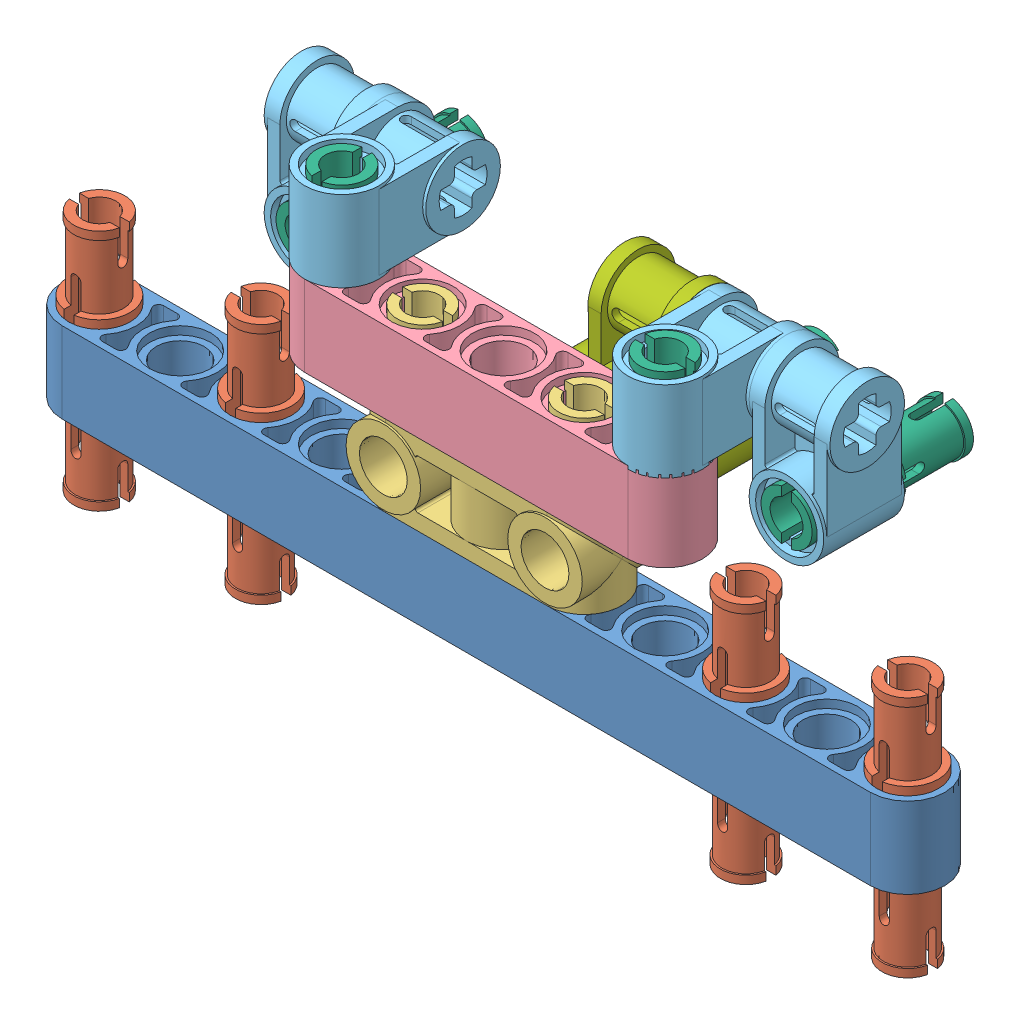
SolidWorks assembly NXT Mount LH, configuration Default. Lengths in mm.
Overall size (88.09 40.29 24.07).
17 component instances, 7 part files, 43 mates.
Components (placement in the parent):
- beam_11-1: beam_11 [Default] at (-40.325 -4.0325 0) size (88.09 8.06 7.44)
- conn_3-1: conn_3 [Default] at (24.195 0.0325 0) size (6.15 24.2 6.07)
- conn_3-2: conn_3 [Default] at (40.325 0.0325 0) x (-1 0 0) z (0 0 -1) size (6.15 24.2 6.07)
- conn_3-3: conn_3 [Default] at (-40.325 0.0325 0) size (6.15 24.2 6.07)
- conn_3-4: conn_3 [Default] at (-24.195 0.0325 0) size (6.15 24.2 6.07)
- conn_3w-1: conn_3w [Default] at (0 8.065 -3.72) x (0 1 0) z (1 0 0) size (24.2 7.85 23.57)
- beam_5-1: beam_5 [Default] at (-16.13 20.1625 0) x (1 0 0) z (0 0 -1) size (39.7 8.06 7.44)
- crossblock_2-1: crossblock_2 [Default] at (-24.195 20.1625 -11.785) x (0 1 0) z (1 0 0) size (15.5 8.06 8.06)
- crossblock_2-2: crossblock_2 [Default] at (16.13 20.1625 -4.0325) x (0 0 -1) z (1 0 0) size (15.5 8.06 8.06)
- crossblock_2-3: crossblock_2 [Default] at (-16.13 20.475 -4.0325) x (0 0 -1) z (1 0 0) size (15.5 8.06 8.06)
- crossblock_2-4: crossblock_2 [Default] at (24.195 19.85 -11.785) x (0 1 0) z (1 0 0) size (15.5 8.06 8.06)
- conn-1: conn [Default] at (24.195 15.8175 -12.0975) x (0 1 0) z (1 0 0) size (6.15 16.1 6.07)
- conn-2: conn [Default] at (-16.13 20.1625 0) x (0 0 1) z (1 0 0) size (6.15 16.1 6.07)
- conn-3: conn [Default] at (16.13 20.1625 0) size (6.15 16.1 6.07)
- conn-4: conn [Default] at (-24.195 16.13 -12.0975) x (0 1 0) z (1 0 0) size (6.15 16.1 6.07)
- crossblock-1: crossblock [Default] at (8.065 15.8175 -8.065) x (1 0 0) z (0 -1 0) size (15.5 8.06 15.51)
- conn-5: conn [Default] at (12.0975 15.8175 -11.3708) x (0.865085 0.501625 0) z (0.501625 -0.865085 0) size (6.15 16.1 6.07)
Mates (geometry in assembly coordinates):
- Concentric54: concentric anti-aligned: cylinder of beam_11-1 through (-8.065 -3.2175 0) axis (0 1 0) radius 2.39; cylinder of conn_3w-1 through (-8.065 3.2175 0) axis (0 -1 0) radius 2.39
- Concentric55: concentric anti-aligned: cylinder of beam_11-1 through (8.065 -3.2175 0) axis (0 1 0) radius 2.39; cylinder of conn_3w-1 through (8.065 3.2175 0) axis (0 -1 0) radius 2.39
- Coincident53: coincident anti-aligned: plane of beam_11-1 through (-45.8068 4.0325 3.8688) normal (0 1 0); plane of conn_3w-1 through (-12.2603 4.0325 -3.8688) normal (0 -1 0)
- Coincident141: coincident anti-aligned: circle of beam_11-1; circle of conn_3-2
- Coincident142: coincident anti-aligned: circle of beam_11-1; circle of conn_3-1
- Coincident143: coincident anti-aligned: circle of beam_11-1; circle of conn_3-4
- Coincident144: coincident anti-aligned: circle of beam_11-1; circle of conn_3-3
- Parallel68: parallel anti-aligned: plane of beam_11-1 through (-40.325 -4.0325 0) normal (0 0 1); plane of conn_3-2 through (40.325 0.0325 0) normal (0 0 -1)
- Parallel69: parallel aligned: plane of beam_11-1 through (-40.325 -4.0325 0) normal (0 0 1); plane of conn_3-3 through (-40.325 0.0325 0) normal (0 0 1)
- Parallel70: parallel aligned: plane of beam_11-1 through (-40.325 -4.0325 0) normal (0 0 1); plane of conn_3-4 through (-24.195 0.0325 0) normal (0 0 1)
- Concentric56: concentric aligned: cylinder of beam_5-1 through (-8.065 19.3475 0) axis (0 -1 0) radius 2.39; cylinder of conn_3w-1 through (-8.065 19.3475 0) axis (0 -1 0) radius 2.39
- Concentric57: concentric aligned: cylinder of conn_3w-1 through (8.065 19.3475 0) axis (0 -1 0) radius 2.39; cylinder of beam_5-1 through (8.065 19.3475 0) axis (0 -1 0) radius 2.39
- Coincident54: coincident anti-aligned: plane of conn_3w-1 through (12.2603 12.0975 -3.8688) normal (0 1 0); plane of beam_5-1 through (-20.6501 12.0975 -3.8688) normal (0 -1 0)
- Parallel14: parallel aligned: plane of conn_3w-1 through (12.2564 4.1962 -3.925) normal (0 0 -1); plane of crossblock_2-4 through (28.0677 11.9487 -12.0975) normal (0 0 -1)
- Parallel15: parallel aligned: plane of conn_3w-1 through (12.2564 4.1962 -3.925) normal (0 0 -1); plane of crossblock_2-1 through (-20.3223 12.2612 -12.0975) normal (0 0 -1)
- Parallel17: parallel aligned: plane of conn_3w-1 through (12.2564 4.1962 -3.925) normal (0 0 -1); plane of crossblock-1 through (-0.0013 11.9478 -12.0975) normal (0 0 -1)
- Concentric71: concentric anti-aligned: cylinder of beam_5-1 through (16.13 19.3475 0) axis (0 -1 0) radius 2.39; cylinder of crossblock_2-2 through (16.13 20.665 0) axis (0 1 0) radius 2.39
- Coincident71: coincident anti-aligned: plane of beam_5-1 through (-20.6501 20.1625 -3.8688) normal (0 1 0); plane of crossblock_2-2 through (19.9988 20.1625 0.1613) normal (0 -1 0)
- Concentric72: concentric anti-aligned: cylinder of beam_5-1 through (-16.13 19.3475 0) axis (0 -1 0) radius 2.39; cylinder of crossblock_2-3 through (-16.13 20.9775 0) axis (0 1 0) radius 2.39
- Coincident72: coincident anti-aligned: plane of beam_5-1 through (-20.6501 20.1625 -3.8688) normal (0 1 0); plane of crossblock_2-3 through (-12.2573 20.1625 3.8688) normal (0 -1 0)
- Coincident166: coincident anti-aligned: circle of beam_5-1; circle of conn-3
- Coincident167: coincident aligned: circle of beam_5-1; circle of conn-2
- Concentric74: concentric anti-aligned: circle of crossblock_2-1; circle of crossblock_2-3
- Coincident78: coincident anti-aligned: plane of crossblock_2-1 through (-20.1625 20.3262 -11.9377) normal (1 0 0); plane of crossblock_2-3 through (-20.1625 20.3223 -4.1962) normal (-1 0 0)
- Coincident160: coincident aligned: circle of crossblock_2-1; circle of conn-4
- Parallel13: parallel anti-aligned: plane of crossblock_2-2 through (12.0975 20.0098 -4.1962) normal (-1 0 0); plane of crossblock_2-3 through (-12.0975 20.3223 -4.1962) normal (1 0 0)
- Concentric73: concentric anti-aligned: circle of crossblock_2-2; circle of crossblock_2-4
- Coincident75: coincident anti-aligned: plane of crossblock_2-2 through (20.1625 20.0098 -4.1962) normal (1 0 0); plane of crossblock_2-4 through (20.1625 20.0137 -11.9377) normal (-1 0 0)
- Coincident79: coincident aligned: cylinder of conn-3 through (16.13 12.9275 0) axis (0 1 0) radius 2.39; circle of crossblock_2-2
- Concentric82: concentric aligned: circle of crossblock_2-2; circle of crossblock-1
- Coincident81: coincident anti-aligned: plane of crossblock_2-2 through (12.0975 20.0098 -4.1962) normal (-1 0 0); plane of crossblock-1 through (12.0975 20.6845 -11.267) normal (1 0 0)
- Concentric75: concentric anti-aligned: cylinder of crossblock_2-3 through (-16.13 20.9775 0) axis (0 1 0) radius 2.39; cylinder of conn-2 through (-16.13 27.3975 0) axis (0 -1 0) radius 2.39
- Coincident161: coincident aligned: circle of crossblock_2-4; circle of conn-1
- Concentric83: concentric aligned: cylinder of crossblock-1 through (12.0975 15.8175 -11.2825) axis (0 0 1) radius 2.39; cylinder of conn-5 through (12.0975 15.8175 -10.5558) axis (0 0 1) radius 2.39
- Lock13: lock: unknown of ?; unknown of ?
- Concentric84: concentric: cylinder of beam_11-1 through (0 -3.2175 0) axis (0 1 0) radius 2.39; point of assembly
- Coincident169: coincident aligned: plane of beam_11-1 through (-40.325 0 0) normal (0 1 0); plane of assembly through (0 0 0) normal (0 1 0)
- Parallel71: parallel aligned: plane of beam_11-1 through (-40.325 -4.0325 0) normal (0 0 1); plane of assembly through (0 0 0) normal (0 0 1)
- Parallel72: parallel aligned: plane of conn_3-1 through (24.195 0.0325 0) normal (0 0 1); plane of assembly through (0 0 0) normal (0 0 1)
- Parallel73: parallel aligned: plane of conn-1 through (24.195 15.8175 -12.0975) normal (1 0 0); plane of assembly through (0 0 0) normal (1 0 0)
- Parallel74: parallel aligned: plane of conn-2 through (-16.13 20.1625 0) normal (1 0 0); plane of assembly through (0 0 0) normal (1 0 0)
- Parallel75: parallel aligned: plane of conn-3 through (16.13 20.1625 0) normal (0 0 1); plane of assembly through (0 0 0) normal (0 0 1)
- Parallel76: parallel aligned: plane of conn-4 through (-24.195 16.13 -12.0975) normal (1 0 0); plane of assembly through (0 0 0) normal (1 0 0)
